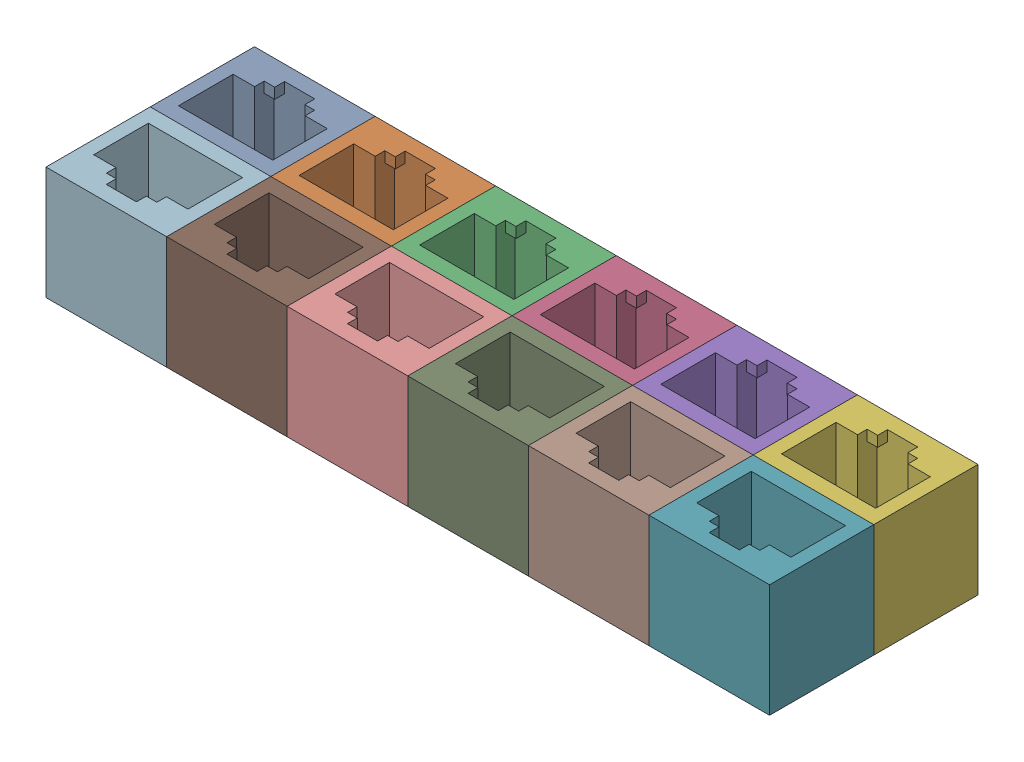
SolidWorks assembly 12-port block, configuration Default. Lengths in mm.
Overall size (96 15 27.66).
14 component instances, 1 part files, 3 mates.
Components (placement in the parent):
- 6-port block-1: 6-port block [Default] at (18.7671 16.9181 15.9423) size (96 15 13.83)
  - RJ45 dummy jack trimmed-1: RJ45 dummy jack trimmed [Default] at (-42.6786 6.807 34.1283) size (16 15 13.83)
  - RJ45 dummy jack trimmed-2: RJ45 dummy jack trimmed [Default] at (-26.6786 6.807 34.1283) size (16 15 13.83)
  - RJ45 dummy jack trimmed-3: RJ45 dummy jack trimmed [Default] at (-10.6786 6.807 34.1283) size (16 15 13.83)
  - RJ45 dummy jack trimmed-4: RJ45 dummy jack trimmed [Default] at (5.3214 6.807 34.1283) size (16 15 13.83)
  - RJ45 dummy jack trimmed-5: RJ45 dummy jack trimmed [Default] at (21.3214 6.807 34.1283) size (16 15 13.83)
  - RJ45 dummy jack trimmed-6: RJ45 dummy jack trimmed [Default] at (37.3214 6.807 34.1283) size (16 15 13.83)
- 6-port block-2: 6-port block [Default] at (25.9098 16.9181 88.1988) x (-1 0 0) z (0 0 -1) size (96 15 13.83)
  - RJ45 dummy jack trimmed-1: RJ45 dummy jack trimmed [Default] at (-42.6786 6.807 34.1283) size (16 15 13.83)
  - RJ45 dummy jack trimmed-2: RJ45 dummy jack trimmed [Default] at (-26.6786 6.807 34.1283) size (16 15 13.83)
  - RJ45 dummy jack trimmed-3: RJ45 dummy jack trimmed [Default] at (-10.6786 6.807 34.1283) size (16 15 13.83)
  - RJ45 dummy jack trimmed-4: RJ45 dummy jack trimmed [Default] at (5.3214 6.807 34.1283) size (16 15 13.83)
  - RJ45 dummy jack trimmed-5: RJ45 dummy jack trimmed [Default] at (21.3214 6.807 34.1283) size (16 15 13.83)
  - RJ45 dummy jack trimmed-6: RJ45 dummy jack trimmed [Default] at (37.3214 6.807 34.1283) size (16 15 13.83)
Mates (geometry in assembly coordinates):
- Coincident1: coincident: point of assembly; point of assembly; moEndPointRef_w of 6-port block-1/RJ45 dummy jack trimmed-1; moEndPointRef_w of 6-port block-2/RJ45 dummy jack trimmed-6
- Coincident2: coincident: plane of 6-port block-1/RJ45 dummy jack trimmed-6 through (54.3385 48.7251 52.0705) normal (0 0 1); plane of 6-port block-2/RJ45 dummy jack trimmed-1 through (70.3385 48.7251 52.0705) normal (0 0 -1)
- Coincident3: coincident: unknown of 6-port block-1/RJ45 dummy jack trimmed-6; unknown of 6-port block-2/RJ45 dummy jack trimmed-1
